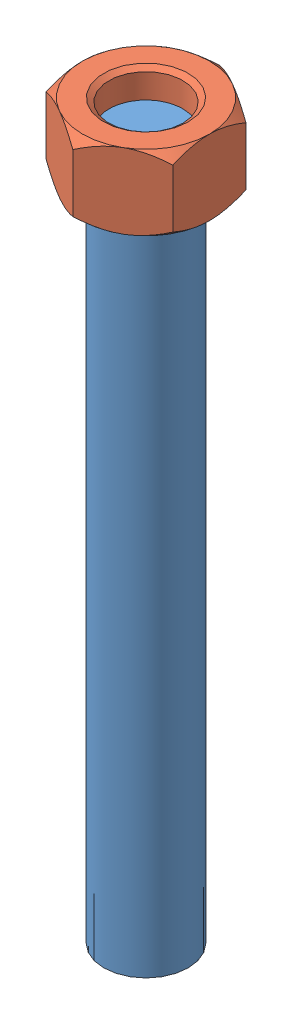
SolidWorks assembly 01-117-00-0, configuration Default. Lengths in mm.
Overall size (28.57 165.1 33).
2 component instances, 2 part files, 2 mates.
Components (placement in the parent):
- TROD 0.7500-1x6.25-1: TROD 0.7500-1x6.25 [Default] at origin size (19.05 158.75 19.05)
- hex nut_ai-1: hex nut_ai [HNUT 0.7500-10-D-C] at (0 165.1 0) x (1 0 0) z (0 1 0) size (28.57 33 16.89)
Mates (geometry in assembly coordinates):
- Concentric1: concentric anti-aligned: cylinder of TROD 0.7500-1x6.25-1 through (0 158.75 0) axis (0 -1 0) radius 9.525; cylinder of hex nut_ai-1 through (0 148.209 0) axis (0 1 0) radius 8.3337
- Distance1: distance = 6.35 mm aligned: plane of hex nut_ai-1 through (0 165.1 -16.4978) normal (0 1 0); plane of TROD 0.7500-1x6.25-1 through (0 158.75 0) normal (0 1 0)
